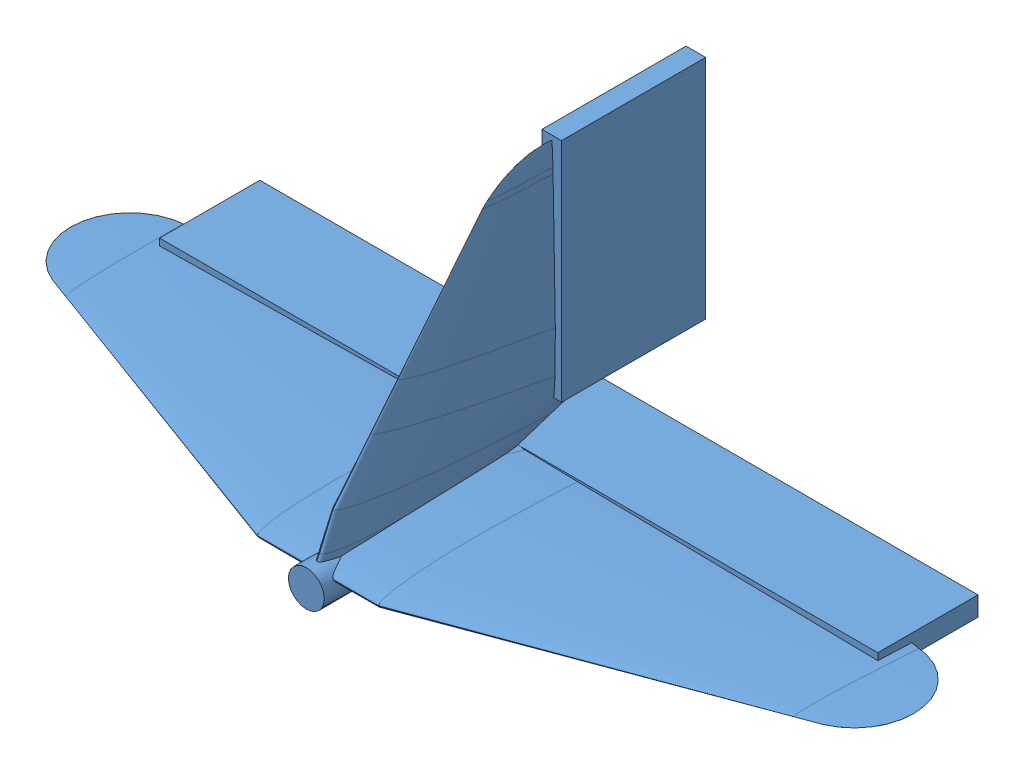
SolidWorks assembly tail_assembly, configuration Default. Lengths in mm.
Overall size (516.5 207.85 855.44).
3 component instances, 3 part files, 6 mates.
Components (placement in the parent):
- cut_tail-1: cut_tail [Default] at (-18.9134 -87.7395 393.2972) size (516.5 210.34 888.63)
- elevator-1: elevator [Default] at (-18.9134 -87.7395 393.2972) size (440 9.46 58.87)
- rudder-1: rudder [Default] at (-18.9134 -87.7395 393.2972) size (4.41 136.11 58.92)
Mates (geometry in assembly coordinates):
- Parallel1: parallel: plane of cut_tail-1 through (-238.9134 -74.5122 -316.7985) normal (0 0 -1); plane of elevator-1 through (109.0687 -64.1163 -336.3304) normal (0 0 1)
- Coincident2: coincident: plane of cut_tail-1 through (201.0866 -74.5122 -316.7985) normal (-1 0 0); plane of elevator-1 through (201.0866 -73.2534 -335.3304) normal (1 0 0)
- Parallel2: parallel: plane of cut_tail-1 through (-24.9134 -46.8957 -337.0188) normal (0 0 -1); plane of rudder-1 through (-21.0635 -22.0825 -338.0188) normal (0 0 1)
- Coincident4: coincident: plane of cut_tail-1 through (-24.9134 -46.8957 -425.3531) normal (0 1 0); plane of rudder-1 through (-24.9134 -46.8957 -425.3531) normal (0 -1 0)
- Coincident5: coincident: point of cut_tail-1
- Coincident6: coincident: unknown of cut_tail-1
